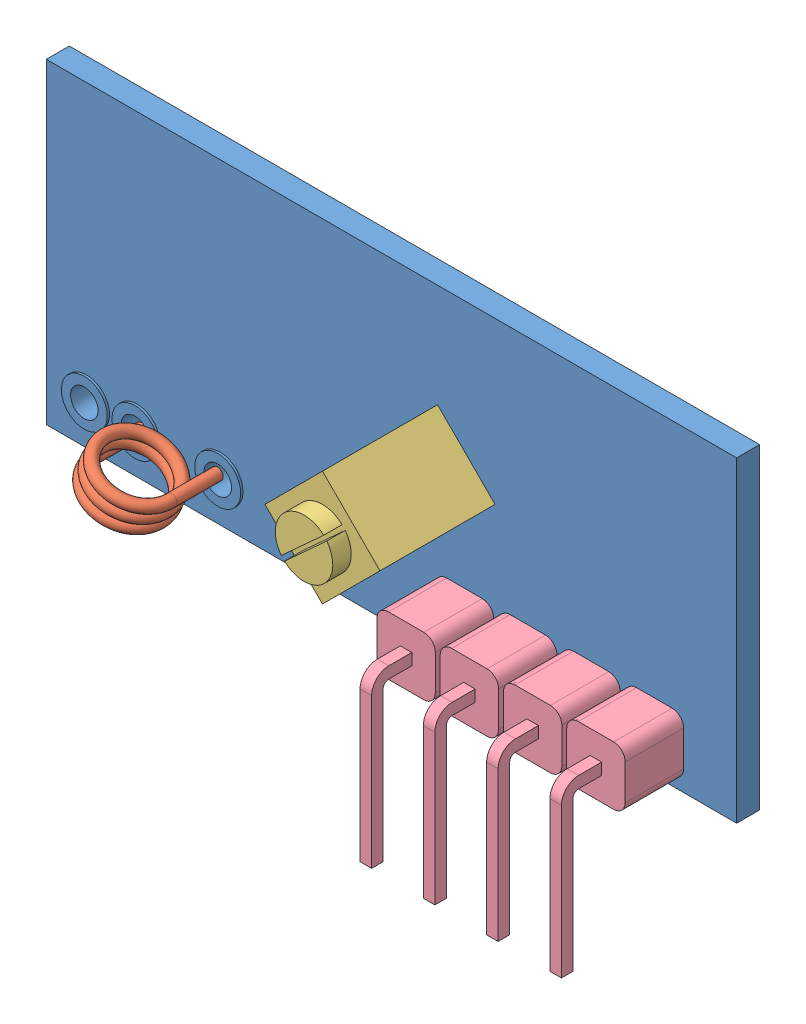
SolidWorks assembly 433MhzRX, configuration Défaut. Lengths in mm.
Overall size (30 19.01 6.8).
10 component instances, 4 part files, 0 mates.
Components (placement in the parent):
- 433MhzRX.iges-1: 433MhzRX.iges [Défaut] at origin size (30 19.01 6.8)
  - 433 OOK Receiver.iges-1: 433 OOK Receiver.iges [Défaut] at origin size (30 19.01 6.8)
    - pcb.iges-1: pcb.iges [Défaut] at origin size (30 13.75 1.1)
    - small coil v1.iges-1: small coil v1.iges [Défaut] at (-21.2443 -21.3088 -0.1406) x (0.939693 0.34202 0) z (0.34202 -0.939693 0) size (3.59 4.14 3.27)
    - Frequency Selector.iges-1: Frequency Selector.iges [Défaut] at origin size (5 5 5.8)
    - Pin Headers.iges-1: Pin Headers.iges [Défaut] at origin size (10.79 8.27 4.29)
      - Pin Header Bendt v1.iges-1: Pin Header Bendt v1.iges [Défaut] at (-0.55 -6.5006 0.0858) x (1 0 0) z (0 -1 0) size (2.54 4.29 8.27)
      - Pin Header Bendt v1.iges-2: Pin Header Bendt v1.iges [Défaut] at (-3.3 -6.5006 0.0858) x (1 0 0) z (0 -1 0) size (2.54 4.29 8.27)
      - Pin Header Bendt v1.iges-3: Pin Header Bendt v1.iges [Défaut] at (-6.05 -6.5006 0.0858) x (1 0 0) z (0 -1 0) size (2.54 4.29 8.27)
      - Pin Header Bendt v1.iges-4: Pin Header Bendt v1.iges [Défaut] at (-8.8 -6.5006 0.0858) x (1 0 0) z (0 -1 0) size (2.54 4.29 8.27)
